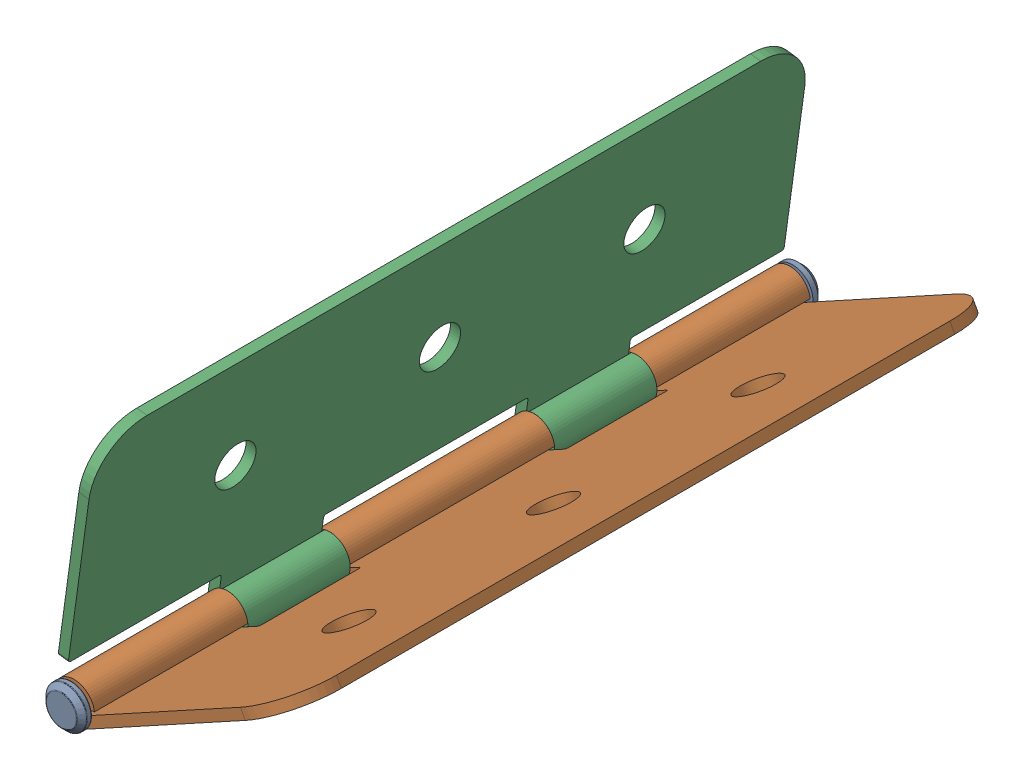
SolidWorks assembly Hinge Assembly, configuration Default. Lengths in mm.
Overall size (119.23 128.87 362.5).
3 component instances, 3 part files, 4 mates.
Components (placement in the parent):
- Pin for Door-1: Pin for Door [Default] at origin size (20 20 362.5)
- Door Hinge-1: Door Hinge [Default] at (55.6601 24.1734 35.0125) x (0 0 -1) z (-0.480619 0.87693 0) size (350 125 20)
- Door Hinge Part 2-1: Door Hinge Part 2 [Default] at (2.9683 68.0626 -34.9875) x (0 0 1) z (0.990734 -0.135813 0) size (350 125 20)
Mates (geometry in assembly coordinates):
- Concentric2: concentric anti-aligned: cylinder of Pin for Door-1 through (0 0 176.2625) axis (0 0 -1) radius 4.625; cylinder of Door Hinge-1 through (0 0 50.0125) axis (0 0 1) radius 5
- Width1: width aligned: plane of Pin for Door-1 through (0 0 176.2625) normal (0 0 -1); plane of Door Hinge-1 through (0 0 -176.2375) normal (0 0 1); plane of Pin for Door-1 through (-3.9631 -13.5755 -174.9875) normal (0 0 -1); plane of Door Hinge-1 through (105.6531 46.5019 175.0125) normal (0 0 1)
- Hinge1: hinge anti-aligned: cylinder of Door Hinge Part 2-1 through (0 0 50.0125) axis (0 0 -1) radius 5; cylinder of Door Hinge Part 2-1 through (0 0 50.0125) axis (0 0 1) radius 5; plane of Door Hinge-1 through (0 0 -99.9875) normal (0 0 -1); plane of Door Hinge-1 through (0 0 -99.9875) normal (0 0 1)
- LimitAngle2: limit planar angle = 0.933202 rad anti-aligned: plane of Door Hinge Part 2-1 through (10.6649 114.6135 -174.9875) normal (0.990734 -0.135813 0); plane of Door Hinge-1 through (103.25 50.8865 175.0125) normal (-0.480619 0.87693 0)
